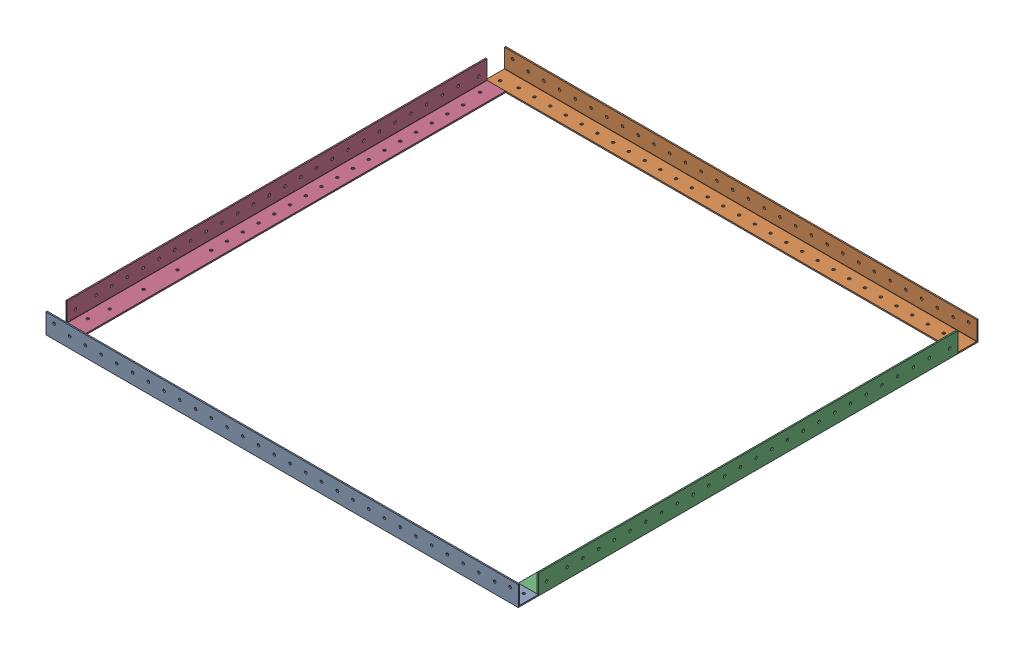
SolidWorks assembly Bottom Half Subassembly, configuration Default. Lengths in mm.
Overall size (600 25.4 584).
4 component instances, 3 part files, 15 mates.
Components (placement in the parent):
- 600mm L Angle-1: 600mm L Angle [8982K556] at (-705.4187 279.8357 168.1298) x (0 0 -1) z (1 0 0) size (25.4 25.4 600)
- 600mm L Angle-2: 600mm L Angle [8982K556] at (1132.9813 279.8357 -415.8702) x (0 0 1) z (-1 0 0) size (25.4 25.4 600)
- 584 mm L Angle-2: 584 mm L Angle [8982K556] at (513.7813 279.8357 -1076.4702) x (0 1 0) z (0 0 1) size (25.4 25.4 533.2)
- 584 mm Top Front L Angle-1: 584 mm Top Front L Angle [8982K556] at (-86.2187 279.8357 828.7298) x (0 1 0) z (0 0 -1) size (25.4 25.4 533.2)
Mates (geometry in assembly coordinates):
- Coincident1: coincident anti-aligned: plane of 584 mm L Angle-1 through (66.3675 119.3526 493.2924) normal (0 0 1); plane of 600mm L Angle-1 through (513.7813 279.8357 142.7298) normal (0 0 -1)
- Coincident2: coincident aligned: plane of 584 mm L Angle-1 through (66.3675 144.7526 493.2924) normal (-1 0 0); plane of 600mm L Angle-1 through (-86.2187 279.8357 108.1298) normal (-1 0 0)
- Coincident3: coincident aligned: plane of 584 mm L Angle-1 through (91.7675 120.9401 493.2924) normal (0 1 0); plane of 600mm L Angle-1 through (513.7813 281.4232 142.7298) normal (0 1 0)
- Coincident4: coincident anti-aligned: plane of 584 mm L Angle-1 through (126.3675 119.3526 -39.9076) normal (0 0 -1); plane of 600mm L Angle-2 through (-86.2187 279.8357 -390.4702) normal (0 0 1)
- Coincident5: coincident aligned: plane of 584 mm L Angle-1 through (91.7675 120.9401 493.2924) normal (0 1 0); plane of 600mm L Angle-2 through (-86.2187 281.4232 -390.4702) normal (0 1 0)
- Coincident6: coincident aligned: plane of 584 mm L Angle-1 through (66.3675 144.7526 493.2924) normal (-1 0 0); plane of 600mm L Angle-2 through (-86.2187 279.8357 -415.8702) normal (-1 0 0)
- Coincident7: coincident aligned: plane of 600mm L Angle-1 through (513.7813 281.4232 142.7298) normal (0 1 0); plane of 584 mm L Angle-2 through (512.1938 281.4232 142.7298) normal (0 1 0)
- Coincident8: coincident aligned: plane of 600mm L Angle-2 through (513.7813 279.8357 -355.8702) normal (1 0 0); plane of 584 mm L Angle-2 through (513.7813 279.8357 142.7298) normal (1 0 0)
- Coincident9: coincident anti-aligned: plane of 600mm L Angle-1 through (513.7813 279.8357 142.7298) normal (0 0 -1); plane of 584 mm L Angle-2 through (513.7813 279.8357 142.7298) normal (0 0 1)
- Coincident10: coincident aligned: plane of 600mm L Angle-1 through (513.7813 281.4232 142.7298) normal (0 1 0); plane of 584 mm Top Front L Angle-1 through (-84.6312 281.4232 -390.4702) normal (0 1 0)
- Coincident11: coincident aligned: plane of 600mm L Angle-1 through (-86.2187 279.8357 108.1298) normal (-1 0 0); plane of 584 mm Top Front L Angle-1 through (-86.2187 279.8357 -390.4702) normal (-1 0 0)
- Coincident12: coincident anti-aligned: plane of 600mm L Angle-2 through (-86.2187 279.8357 -390.4702) normal (0 0 1); plane of 584 mm Top Front L Angle-1 through (-86.2187 279.8357 -390.4702) normal (0 0 -1)
- Coincident13: coincident anti-aligned: plane of 600mm L Angle-1 through (513.7813 279.8357 142.7298) normal (0 0 -1); plane of 584 mm Top Front L Angle-1 through (-47.3596 339.8357 142.7298) normal (0 0 1)
- Coincident14: coincident aligned: plane of 600mm L Angle-1 through (513.7813 279.8357 168.1298) normal (1 0 0); plane of 584 mm L Angle-2 through (513.7813 279.8357 142.7298) normal (1 0 0)
- Coincident15: coincident aligned: plane of 600mm L Angle-2 through (-86.2187 281.4232 -390.4702) normal (0 1 0); plane of 584 mm L Angle-2 through (512.1938 281.4232 142.7298) normal (0 1 0)
